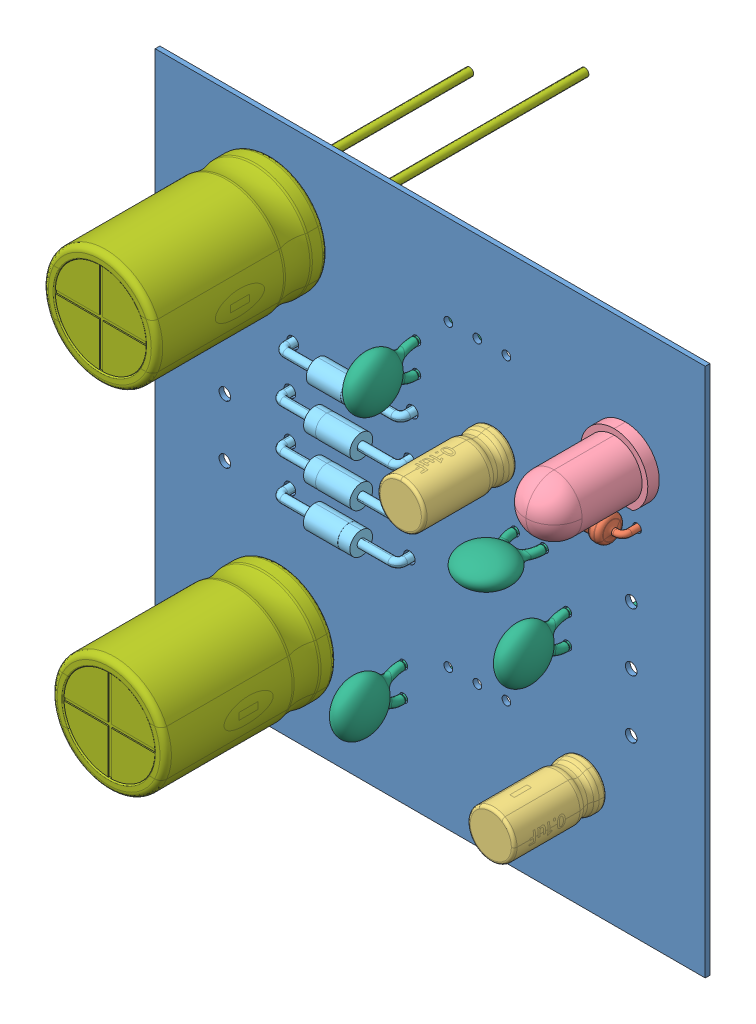
SolidWorks assembly pwr_supply, configuration Default. Lengths in mm.
Overall size (48.13 46.36 39.94).
29 component instances, 7 part files, 6 mates.
Components (placement in the parent):
- PWR_supply_sch.step-1: PWR_supply_sch.step [Default] at origin size (48.13 46.36 17.07)
  - Board.step-1: Board.step [Default] at origin size (48.13 46.36 0.41)
    - Open CASCADE STEP translator 6.8 1.1.1.step-1: Open CASCADE STEP translator 6.8 1.1.1.step [Default] at (0 0 -0.4115) size (48.13 46.36 0.41)
  - R1.step-1: R1.step [Default] at origin size (8.17 2.35 5.67)
    - Resistor_10K_Ohm_tol1pct_0,25W__07,62.step-1: Resistor_10K_Ohm_tol1pct_0,25W__07,62.step [Default] at (77.9779 102.6159 1.27) x (0 -1 0) z (0 0 1) size (2.35 8.17 5.67)
  - C7.step-1: C7.step [Default] at origin size (4.11 4.1 10.61)
    - 0.1uF.step-1: 0.1uF.step [Default] at (77.0889 81.0261 0) x (0 1 0) z (1 0 0) size (4.1 10.61 4.11)
  - LED1.step-1: LED1.step [Default] at origin size (5.93 5.41 12.16)
    - LED_5mm_white_TH.step-1: LED_5mm_white_TH.step [Default] at (81.2801 107.6959 0) x (0 -1 0) z (0 0 1) size (5.41 5.93 12.16)
  - D4.step-1: D4.step [Default] at origin size (11.17 2 4)
    - Diode_(1).step-1: Diode_(1).step [Default] at (58.674 93.98 1.016) x (0 0 -1) z (0 1 0) size (4 11.17 2)
  - D3.step-1: D3.step [Default] at origin size (11.17 2 4)
    - Diode_(1).step-1: Diode_(1).step [Default] at (54.61 90.424 1.016) x (0 0 -1) z (0 -1 0) size (4 11.17 2)
  - D2.step-1: D2.step [Default] at origin size (11.17 2 4)
    - Diode_(1).step-1: Diode_(1).step [Default] at (58.674 97.79 1.016) x (0 0 -1) z (0 1 0) size (4 11.17 2)
  - D1.step-1: D1.step [Default] at origin size (11.17 2 4)
    - Diode_(1).step-1: Diode_(1).step [Default] at (54.864 101.6 1.016) x (0 0 -1) z (0 -1 0) size (4 11.17 2)
  - C8.step-1: C8.step [Default] at origin size (2.5 4.7 14.03)
    - 10pF_Ceramic_Disc_2_RGB8421504.step-1: 10pF_Ceramic_Disc_2_RGB8421504.step [Default] at (75.692 91.948 3.81) x (0 1 0) z (1 0 0) size (4.7 14.03 2.5)
  - C6.step-1: C6.step [Default] at origin size (2.5 4.7 14.03)
    - 10pF_Ceramic_Disc_2_RGB8421504.step-1: 10pF_Ceramic_Disc_2_RGB8421504.step [Default] at (61.341 80.772 3.81) x (0 -1 0) z (-1 0 0) size (4.7 14.03 2.5)
  - C5.step-1: C5.step [Default] at origin size (4.7 2.5 14.03)
    - 10pF_Ceramic_Disc_2_RGB8421504.step-1: 10pF_Ceramic_Disc_2_RGB8421504.step [Default] at (72.39 97.028 3.81) x (1 0 0) z (0 -1 0) size (4.7 14.03 2.5)
  - C4.step-1: C4.step [Default] at origin size (4.1 4.11 10.61)
    - 0.1uF.step-1: 0.1uF.step [Default] at (69.2149 102.1079 0) x (-1 0 0) z (0 1 0) size (4.1 10.61 4.11)
  - C3.step-1: C3.step [Default] at origin size (2.5 4.7 14.03)
    - 10pF_Ceramic_Disc_2_RGB8421504.step-1: 10pF_Ceramic_Disc_2_RGB8421504.step [Default] at (62.484 105.918 3.81) x (0 1 0) z (1 0 0) size (4.7 14.03 2.5)
- 1000uF_16V-1: 1000uF_16V [1000uF_16V] at (49.784 109.982 0) x (0 -1 0) z (-1 0 0) size (10 39.94 10)
- 1000uF_16V-2: 1000uF_16V [Default] at (50.546 79.502 0) x (0 -1 0) z (-1 0 0) size (10 39.94 10)
Mates (geometry in assembly coordinates):
- Concentric1: concentric anti-aligned: cylinder of PWR_supply_sch.step-1/Board.step-1/Open CASCADE STEP translator 6.8 1.1.1.step-1 through (52.324 109.982 -0.4115) axis (0 0 -1) radius 0.4; cylinder of 1000uF_16V-1 through (52.324 109.982 -24.9) axis (0 0 1) radius 0.35
- Concentric2: concentric anti-aligned: cylinder of PWR_supply_sch.step-1/Board.step-1/Open CASCADE STEP translator 6.8 1.1.1.step-1 through (47.244 109.982 -0.4115) axis (0 0 -1) radius 0.4; cylinder of 1000uF_16V-1 through (47.244 109.982 -19.9) axis (0 0 1) radius 0.35
- Coincident1: coincident anti-aligned: plane of PWR_supply_sch.step-1/Board.step-1/Open CASCADE STEP translator 6.8 1.1.1.step-1 through (39.624 71.501 0) normal (0 0 1); circle of 1000uF_16V-1
- Concentric3: concentric anti-aligned: cylinder of PWR_supply_sch.step-1/Board.step-1/Open CASCADE STEP translator 6.8 1.1.1.step-1 through (53.086 79.502 -0.4115) axis (0 0 -1) radius 0.4; cylinder of 1000uF_16V-2 through (53.086 79.502 -24.9) axis (0 0 1) radius 0.35
- Concentric4: concentric anti-aligned: cylinder of PWR_supply_sch.step-1/Board.step-1/Open CASCADE STEP translator 6.8 1.1.1.step-1 through (48.006 79.502 -0.4115) axis (0 0 -1) radius 0.4; cylinder of 1000uF_16V-2 through (48.006 79.502 -19.9) axis (0 0 1) radius 0.35
- Coincident2: coincident anti-aligned: plane of PWR_supply_sch.step-1/Board.step-1/Open CASCADE STEP translator 6.8 1.1.1.step-1 through (39.624 71.501 0) normal (0 0 1); circle of 1000uF_16V-2
